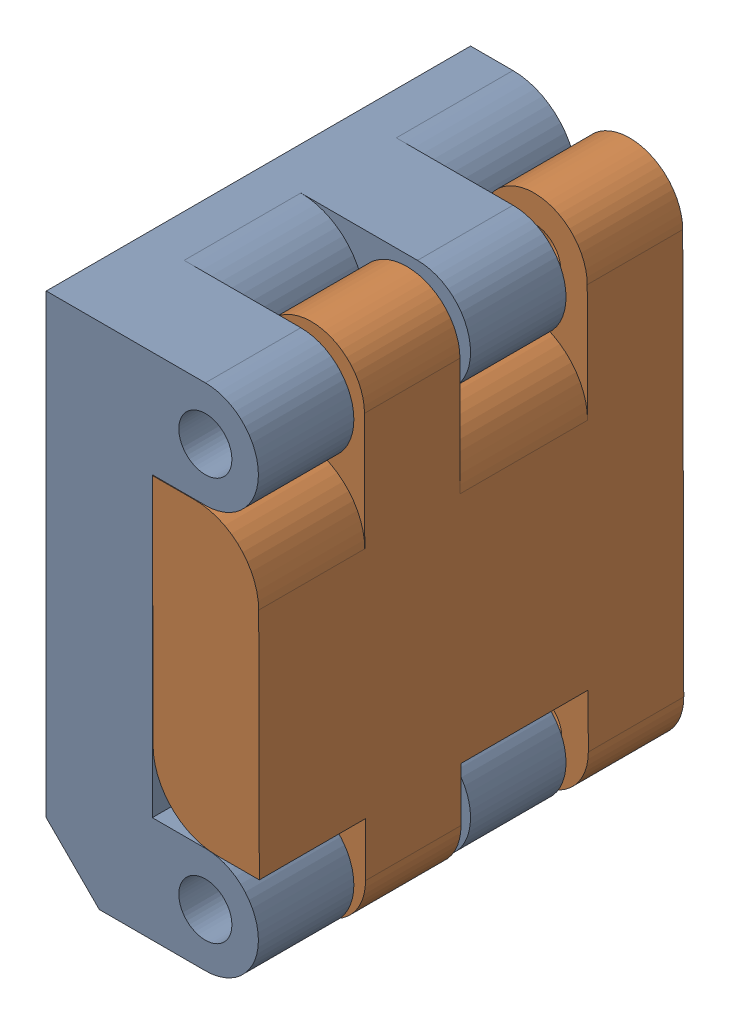
SolidWorks assembly Wing Folder, configuration Default. Lengths in mm.
Overall size (20.11 48.13 40).
2 component instances, 2 part files, 3 mates.
Components (placement in the parent):
- Wing Folder Interior-1: Wing Folder Interior [Default] at origin size (20 48 40)
- Wing Folder Exterior-1: Wing Folder Exterior [Default] at (20.0498 -0.0369 0) x (-0.999997 -0.002614 0) z (0 0 -1) size (10 48.1 40)
Mates (geometry in assembly coordinates):
- Concentric1: concentric anti-aligned: cylinder of Wing Folder Interior-1 through (15 19 -9) axis (0 0 1) radius 2.5; cylinder of Wing Folder Exterior-1 through (15 19 10) axis (0 0 -1) radius 2.5
- Coincident1: coincident aligned: plane of Wing Folder Interior-1 through (10 -24 20) normal (0 0 1); plane of Wing Folder Exterior-1 through (10.0132 13.9369 20) normal (0 0 1)
- Parallel2: parallel aligned: plane of Wing Folder Interior-1 through (10 0 0) normal (1 0 0); plane of Wing Folder Exterior-1
